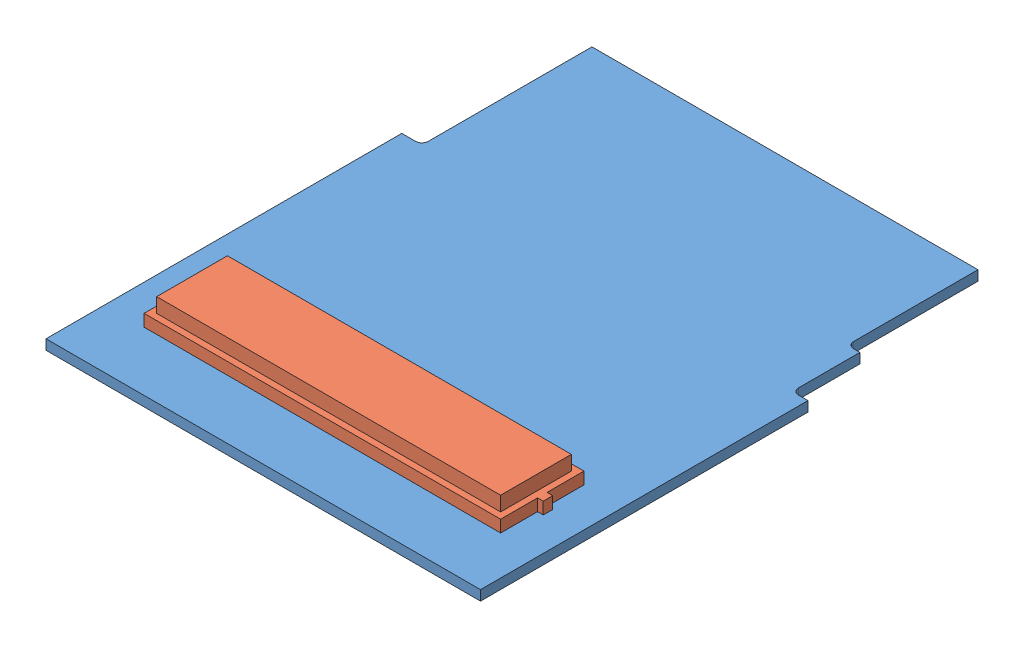
SolidWorks assembly VITA57-FMC, configuration Default. Lengths in mm.
Overall size (69 5.79 83.5).
2 component instances, 2 part files, 3 mates.
Components (placement in the parent):
- VITA57-FMC-PCB-1: VITA57-FMC-PCB [Default] at origin size (69 1.59 83.5)
- VITA57-FMC-male-1: VITA57-FMC-male [8.5mm] at (0 1.5875 0) size (69 4.2 83.5)
Mates (geometry in assembly coordinates):
- Coincident1: coincident anti-aligned: plane of VITA57-FMC-PCB-1 through (33.0019 1.5875 -37) normal (0 1 0); plane of VITA57-FMC-male-1 through (0 1.5875 0) normal (0 -1 0)
- Distance2: distance = 9.385 mm aligned: plane of VITA57-FMC-male-1 through (-28.31 3.4875 6.615) normal (0 0 1); plane of VITA57-FMC-PCB-1 through (-34.5 1.5875 16) normal (0 0 1)
- Coincident3: coincident aligned: line of VITA57-FMC-PCB-1 through (34.5 1.5875 16) axis (0 0 -1); line of VITA57-FMC-male-1 through (34.5 1.5875 9) axis (0 0 -1)
